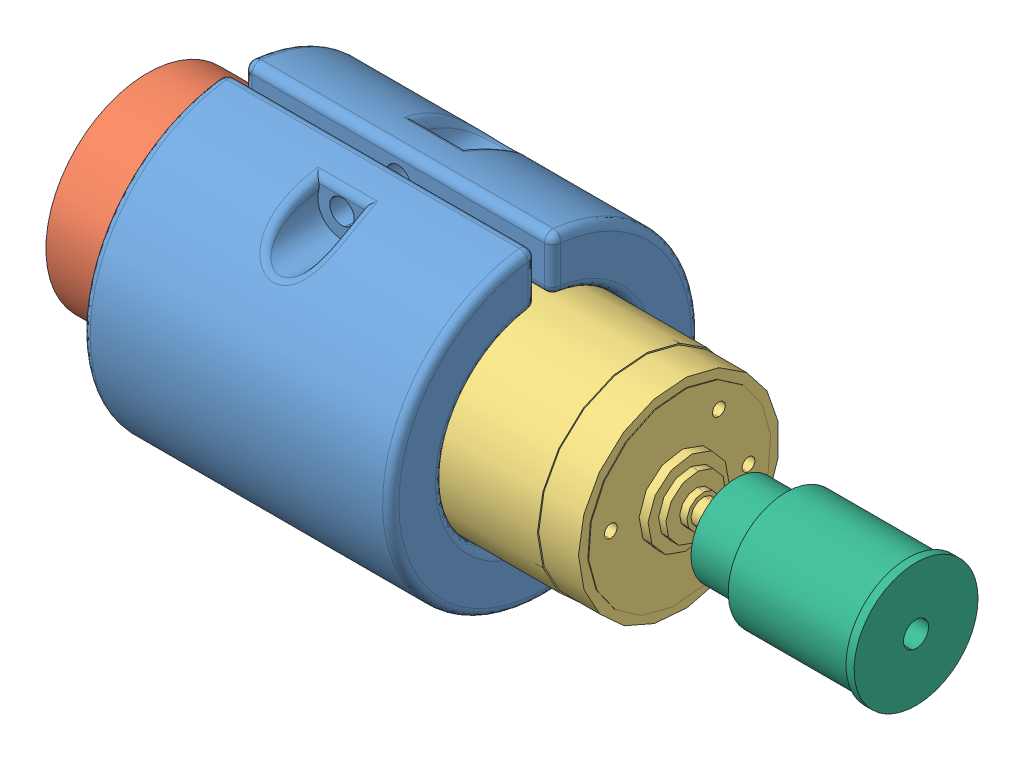
SolidWorks assembly assemblyFinal, configuration Default. Lengths in mm.
Overall size (99.3 38 38).
9 component instances, 6 part files, 1 mates.
Components (placement in the parent):
- holder-1: holder [Default] at (9.9769 23.8946 28.6274) size (38 38 38)
- motorFinal-1: motorFinal [Default] at (-47.8108 8.5118 -27.9533) x (0 0.996753 -0.080522) z (1 0 0) size (25 25 99.3)
  - motorTacho-1: motorTacho [Default] at (-6.3812 44.1785 18.564) size (25 25 83)
    - tacho-1: tacho [Default] at (17.158 13.4571 9.2808) size (25 25 11)
    - 118752-1: 118752 [Default] at (17.158 13.4571 74.7808) x (0 0 -1) z (1 0 0) size (83 25 25)
      - 118752_01-1: 118752_01 [Default] at origin size (83 25 25)
      - 118752_02-1: 118752_02 [Default] at origin size (10.7 2.26 2.26)
      - 118752_03-1: 118752_03 [Default] at origin size (10.7 2.26 2.26)
  - wireCase-1: wireCase [Default] at (10.7768 57.6356 122.4448) x (0.485369 0.874309 0) z (-0.874309 0.485369 0) size (15.25 22.2 15.25)
Mates (geometry in assembly coordinates):
- Concentric1: concentric anti-aligned: cylinder of holder-1 through (-9.0231 23.8946 28.6274) axis (1 0 0) radius 12.5; circle of motorFinal-1/motorTacho-1/118752-1/118752_01-1
